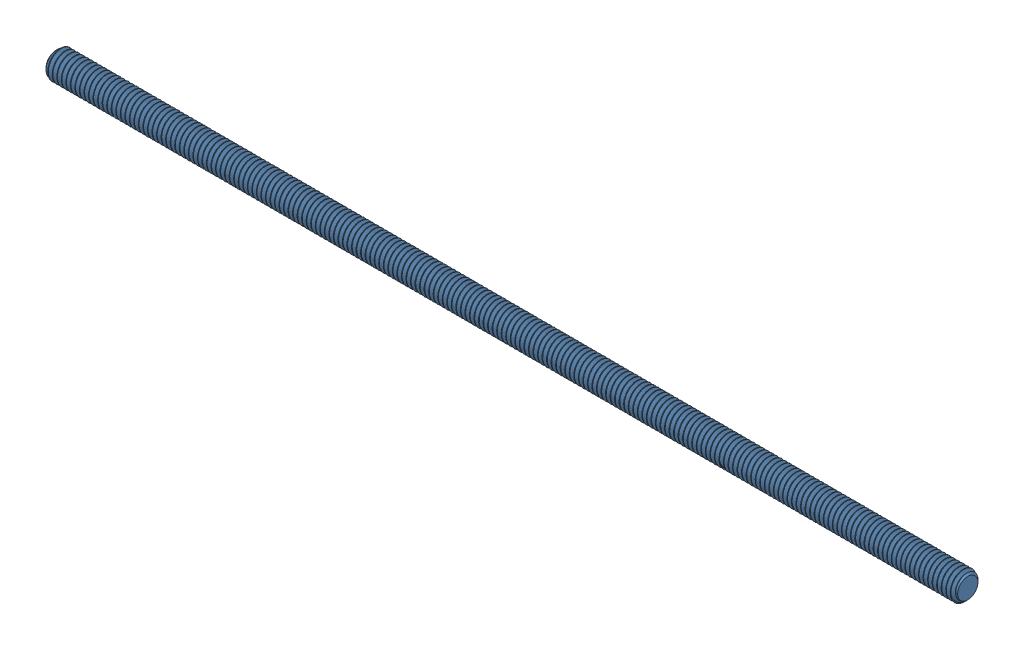
SolidWorks assembly M_M3_ThreadedRod, configuration Default. Lengths in mm.
Overall size (101.43 3.04 3.46).
2 component instances, 1 part files, 2 mates.
Components (placement in the parent):
- 90024A220_18-8 STAINLESS STEEL THREADED ROD-1: 90024A220_18-8 STAINLESS STEEL THREADED ROD [90024A220] at (26.8845 38.7417 59.6923) size (75.94 3.04 3.46)
- 90024A220_18-8 STAINLESS STEEL THREADED ROD-2: 90024A220_18-8 STAINLESS STEEL THREADED ROD [90024A220] at (52.3745 38.7417 59.6923) size (75.94 3.04 3.46)
Mates (geometry in assembly coordinates):
- Distance1: distance = 100.49 mm anti-aligned: plane of 90024A220_18-8 STAINLESS STEEL THREADED ROD-2 through (89.8745 38.7417 59.6923) normal (1 0 0); plane of 90024A220_18-8 STAINLESS STEEL THREADED ROD-1 through (-10.6155 38.7417 59.6923) normal (-1 0 0)
- Concentric2: concentric aligned: circle of 90024A220_18-8 STAINLESS STEEL THREADED ROD-1; circle of 90024A220_18-8 STAINLESS STEEL THREADED ROD-2
